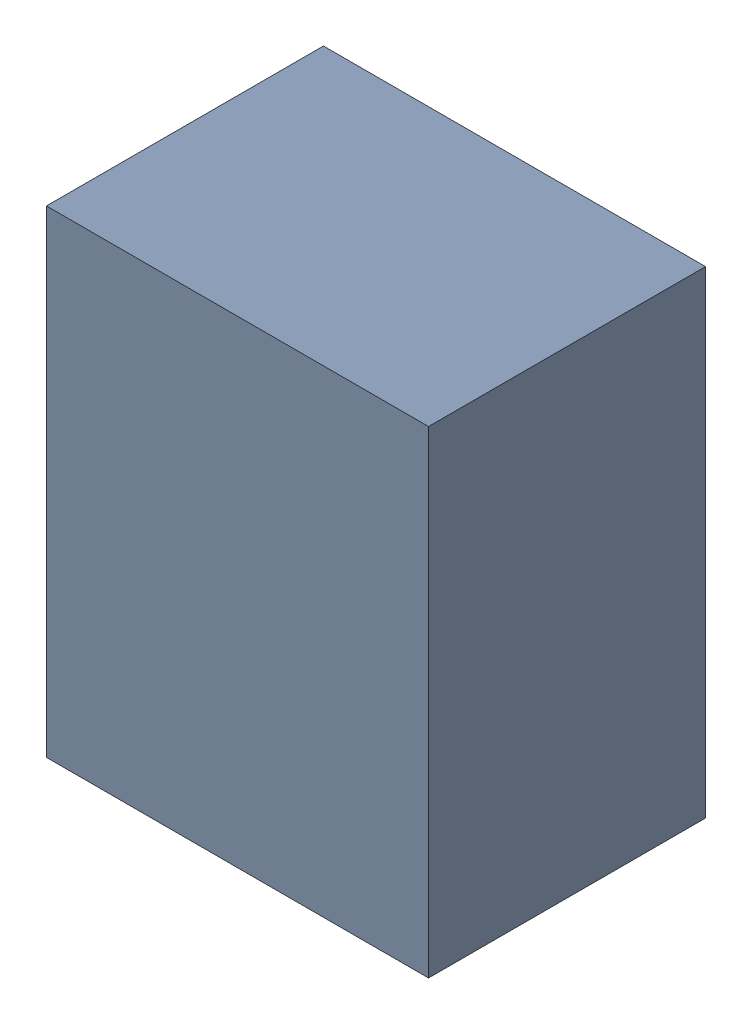
SolidWorks assembly U32, configuration Default. Lengths in mm.
Overall size (0.8 1 0.58).
2 component instances, 1 part files, 0 mates.
Components (placement in the parent):
- 836751984-1: 836751984 [Default] at (133.05 75.15 0.5) size (0.8 1 0.58)
  - Extruded_32-1: Extruded_32 [Default] at origin size (0.8 1 0.58)
